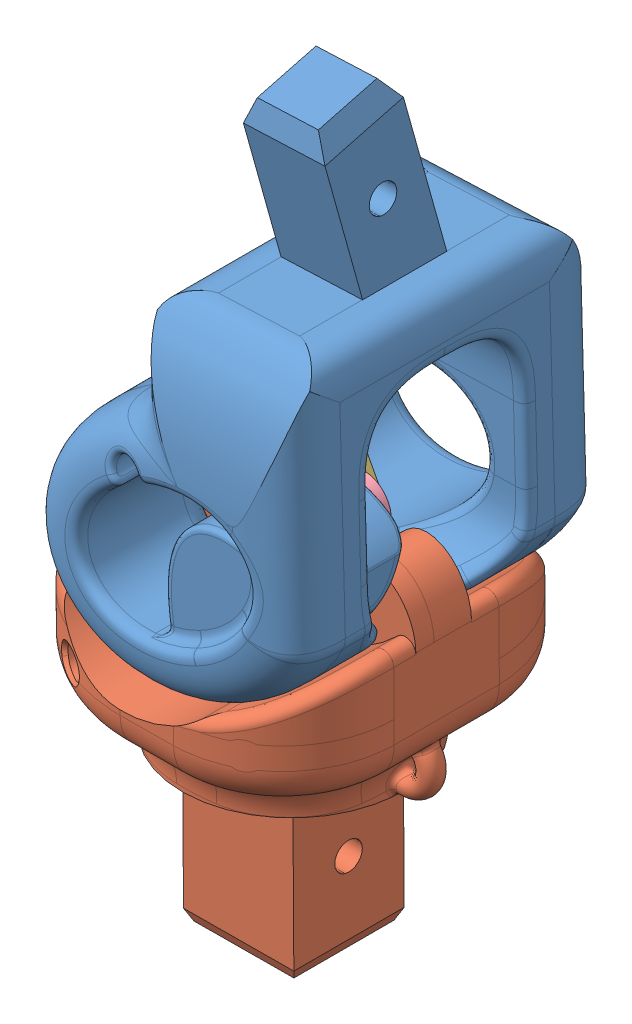
SolidWorks assembly Assem2.51, configuration Default. Lengths in mm.
Overall size (81.67 181.18 79.28).
4 component instances, 4 part files, 26 mates.
Components (placement in the parent):
- Femoral end with hardware - bone connection-1: Femoral end with hardware - bone connection [Default] at (50.9851 52.1944 23.6854) x (-0.999137 -0.04154 0) z (0 0 -1) size (73.59 126.4 79.28)
- Tibial head with hardware - bone connection-1: Tibial head with hardware - bone connection [Default] at (647.7013 154.3898 365.6784) x (0 0 1) z (-0.999979 -0.006457 0) size (75.94 98.43 76.39)
- New link 1-1: New link 1 [Default] at (58.2432 82.8249 10.9854) x (0.881727 0.47176 0) z (0 0 1) size (12.7 64.13 6.35)
- Split link 2-2: Split link 2 [Default] at (49.0234 92.6745 17.3354) x (-0.691162 0.7227 0) z (0 0 1) size (12.7 59.56 6.35)
Mates (geometry in assembly coordinates):
- Coincident2: coincident anti-aligned: plane of ? through (-19.4781 86.0678 0) normal (0 0 -1); plane of ? through (-18.8309 79.2444 0) normal (0 0 1)
- Concentric5: concentric anti-aligned: cylinder of ? through (-0.1367 101.6887 2.54) axis (0 0 -1) radius 3.175; cylinder of ? through (-0.1367 101.6887 -2.54) axis (0 0 1) radius 3.175
- Concentric6: concentric anti-aligned: cylinder of ? through (-5.2167 110.5787 2.54) axis (0 0 -1) radius 3.175; cylinder of ? through (-5.2167 110.5787 2.54) axis (0 0 1) radius 3.175
- Coincident3: coincident anti-aligned: plane of ? through (0 0 0) normal (0 0 -1); plane of ? through (-18.8309 79.2444 0) normal (0 0 1)
- Coincident4: coincident anti-aligned: plane of ? through (0 0 2.54) normal (0 0 1); plane of ? through (-3.5955 78.8701 2.54) normal (0 0 -1)
- Concentric7: concentric aligned: cylinder of ? through (-3.5955 78.8701 0) axis (0 0 1) radius 3.175; cylinder of ? through (-3.5955 78.8701 2.54) axis (0 0 1) radius 3.175
- Concentric8: concentric aligned: cylinder of ? through (-18.8309 79.2444 0) axis (0 0 1) radius 3.175; cylinder of ? through (-18.8309 79.2444 -2.54) axis (0 0 1) radius 3.175
- Concentric9: concentric aligned: cylinder of Femoral end with hardware - bone connection-1 through (40.281 116.3967 -19.4946) axis (0 0 -1) radius 3.175; cylinder of New link 1-1 through (40.281 116.3967 17.3354) axis (0 0 -1) radius 3.937
- Concentric10: concentric anti-aligned: cylinder of Tibial head with hardware - bone connection-1 through (64.546 71.045 -20.7011) axis (0 0 1) radius 3.175; cylinder of New link 1-1 through (64.546 71.045 17.3354) axis (0 0 -1) radius 3.937
- Concentric11: concentric anti-aligned: cylinder of Tibial head with hardware - bone connection-1 through (14.4107 91.3013 -20.7646) axis (0 0 1) radius 3.175; cylinder of ? through (14.4107 91.3013 23.6854) axis (0 0 -1) radius 3.175
- Concentric12: concentric aligned: cylinder of Femoral end with hardware - bone connection-1 through (58.9507 101.6216 46.5454) axis (0 0 -1) radius 3.175; cylinder of ? through (58.9507 101.6216 23.6854) axis (0 0 -1) radius 3.175
- Coincident6: coincident anti-aligned: plane of Tibial head with hardware - bone connection-1 through (70.7728 90.1356 10.9854) normal (0 0 1); plane of New link 1-1 through (40.281 116.3967 10.9854) normal (0 0 -1)
- Coincident7: coincident anti-aligned: plane of Tibial head with hardware - bone connection-1 through (17.3297 110.214 23.6854) normal (0 0 -1); plane of ? through (58.9507 101.6216 23.6854) normal (0 0 1)
- Distance1: distance = 1.524 mm anti-aligned: plane of Femoral end with hardware - bone connection-1 through (40.281 116.3967 9.4614) normal (0 0 1); plane of New link 1-1 through (40.281 116.3967 10.9854) normal (0 0 -1)
- Concentric13: concentric anti-aligned: cylinder of Tibial head with hardware - bone connection-1 through (23.094 71.4484 -20.7011) axis (0 0 1) radius 3.175; cylinder of ? through (23.094 71.4484 23.8124) axis (0 0 -1) radius 3.175
- Coincident9: coincident anti-aligned: plane of Tibial head with hardware - bone connection-1 through (14.9576 85.9595 23.8124) normal (0 0 -1); plane of ? through (58.9508 101.6217 23.8124) normal (0 0 1)
- Concentric14: concentric aligned: cylinder of Femoral end with hardware - bone connection-1 through (58.6787 101.9084 50.9904) axis (0 0 -1) radius 3.175; cylinder of Split link 2-2 through (58.6787 101.9084 23.6854) axis (0 0 -1) radius 3.937
- Coincident23: coincident: plane of ? through (35.382 115.5047 17.4624) normal (0.720266 -0.693698 0); plane of ? through (35.382 115.5047 17.4624) normal (-0.720266 0.693698 0)
- Coincident24: coincident: plane of Split link 2-2; plane of ?
- Coincident25: coincident aligned: plane of ? through (54.8623 106.4804 23.8124) normal (-0.643861 0.765142 0); plane of ? through (54.8622 106.4803 23.8124) normal (-0.643861 0.765142 0)
- Coincident26: coincident aligned: plane of Split link 2-2; plane of ? through (54.8622 106.4803 23.8124) normal (-0.643861 0.765142 0)
- Coincident27: coincident aligned: plane of Split link 2-2 through (23.0938 71.4483 23.8124) normal (0 0 1); plane of ? through (58.9508 101.6216 23.8124) normal (0 0 1)
- Coincident28: coincident aligned: plane of ? through (58.9508 101.6217 23.8124) normal (0 0 1); plane of ? through (58.9508 101.6216 23.8124) normal (0 0 1)
- Concentric15: concentric aligned: cylinder of Femoral end with hardware - bone connection-1 through (58.6787 101.9084 50.9904) axis (0 0 -1) radius 3.175; cylinder of Split link 2-2 through (58.6787 101.9084 23.6854) axis (0 0 -1) radius 3.937
- Concentric16: concentric anti-aligned: cylinder of Tibial head with hardware - bone connection-1 through (24.8108 69.5184 -20.7011) axis (0 0 1) radius 3.175; cylinder of Split link 2-2 through (24.8108 69.5184 23.6854) axis (0 0 -1) radius 3.937
- Coincident29: coincident anti-aligned: plane of Femoral end with hardware - bone connection-1 through (7.5238 60.5414 23.6854) normal (0 0 -1); plane of Split link 2-2 through (24.8108 69.5184 23.6854) normal (0 0 1)
